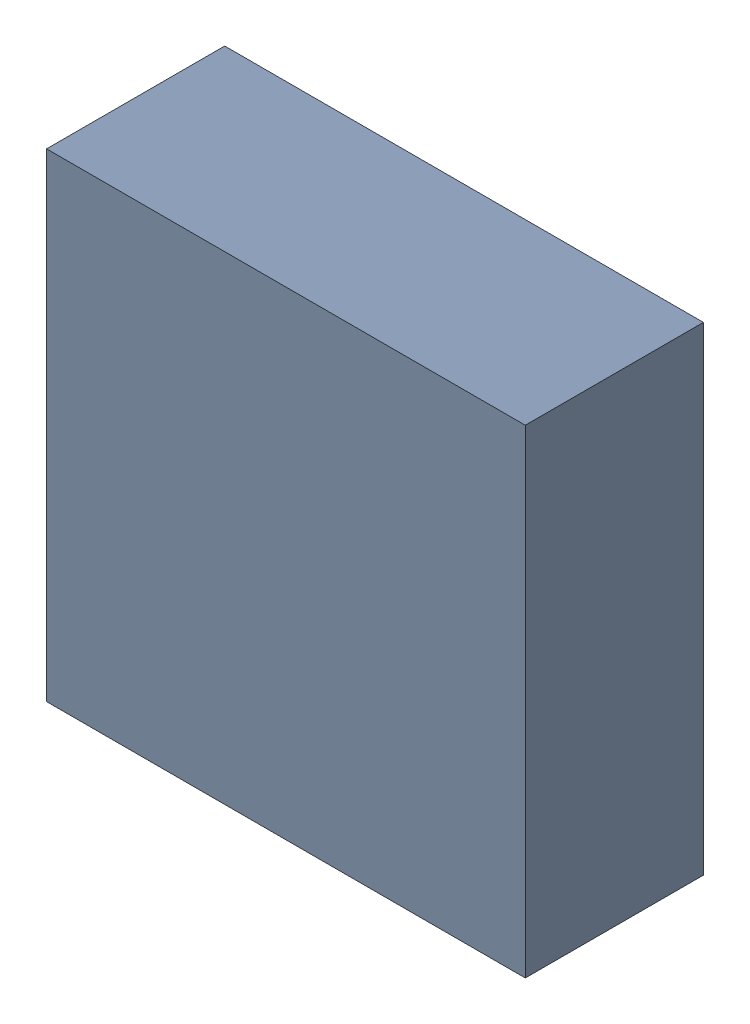
SolidWorks assembly Q5, configuration ﾃﾞﾌｫﾙﾄ. Lengths in mm.
Overall size (2.15 2.15 0.8).
2 component instances, 1 part files, 0 mates.
Components (placement in the parent):
- 689261240-1: 689261240 [ﾃﾞﾌｫﾙﾄ] at (5.3975 14.2875 0) size (2.15 2.15 0.8)
  - Extruded_30-1: Extruded_30 [ﾃﾞﾌｫﾙﾄ] at origin size (2.15 2.15 0.8)
